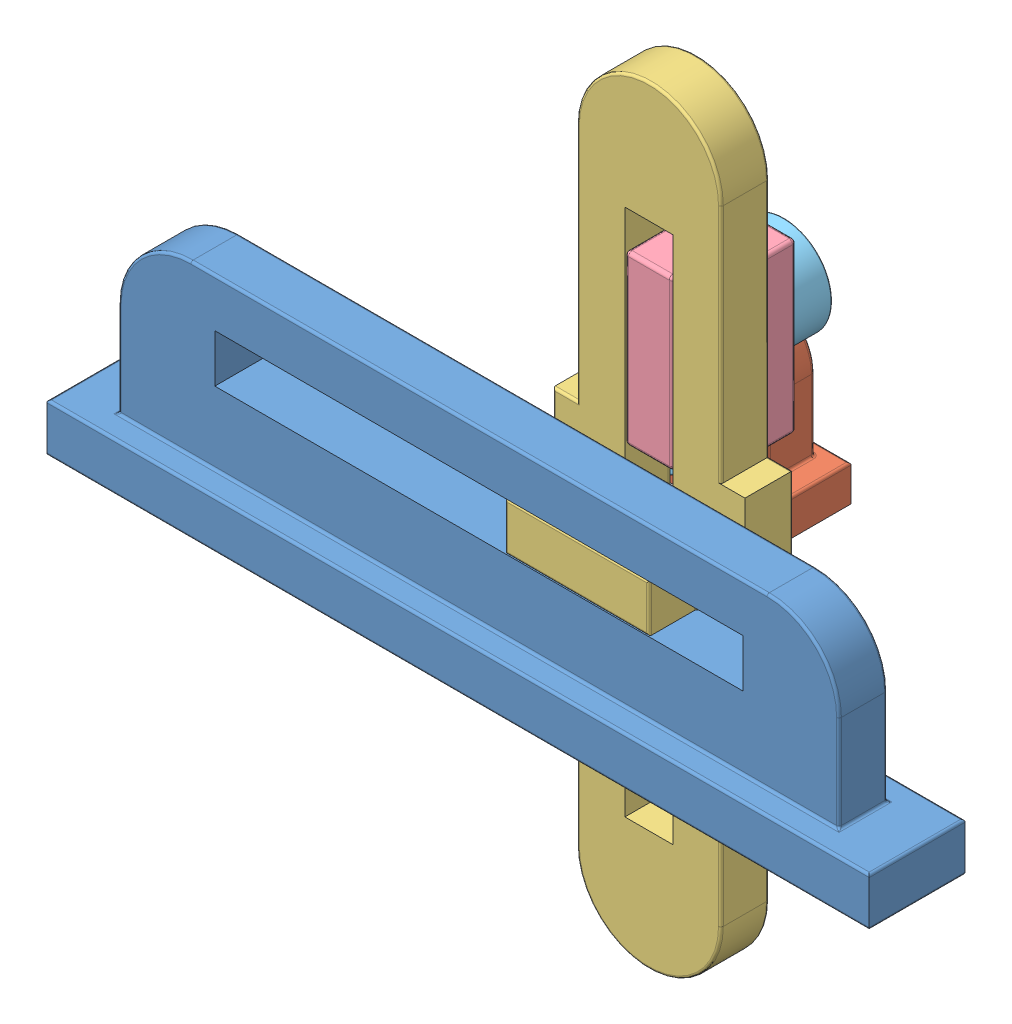
SolidWorks assembly SliderCrank, configuration Default. Lengths in mm.
Overall size (342.57 320 135).
6 component instances, 6 part files, 15 mates.
Components (placement in the parent):
- Slider Body-2: Slider Body [Default] at (60 35 -10) x (1 0 0) z (0 -1 0) size (342.57 40 90)
- Rotor-2: Rotor [Default] at (140 15 -85) x (1 0 0) z (0 -1 0) size (60 30 65)
- Slider-1: Slider [Default] at (210.8163 175 -40) size (80 320 50)
- Connector-2: Connector [Default] at (232.1496 104.3288 -60) x (-1 0 0) z (0 0 -1) size (50 70 60)
- Connecting-rod-2: Connecting-rod [Default] at (207.1496 104.3288 -70) x (0.847554 -0.530708 0) z (0 0 1) size (40 110 20)
- Connecting-Pin-1: Connecting-Pin [Default] at (170 45 -110) x (1 0 0) z (0 -1 0) size (20 50 20)
Mates (geometry in assembly coordinates):
- Coincident2: coincident: plane of Slider Body-2 through (60 35 0) normal (0 0 -1); plane of assembly through (0 0 0) normal (0 0 1)
- Coincident3: coincident: plane of Slider Body-2 through (60 0 -10) normal (0 1 0); plane of assembly through (0 0 0) normal (0 1 0)
- Coincident4: coincident: plane of Slider Body-2 through (0 -15 20) normal (-1 0 0); plane of assembly through (0 0 0) normal (1 0 0)
- Coincident15: coincident: plane of Rotor-2 through (140 0 -85) normal (0 -1 0); plane of assembly through (0 0 0) normal (0 1 0)
- Coincident16: coincident: plane of Slider Body-2 through (170 35 -10) normal (-1 0 0); axis of Rotor-2 through (170 45 -91.5) axis (0 0 -1)
- Coincident17: coincident: plane of Slider Body-2 through (50 45 10) normal (0 0 1); plane of Slider-1 through (210.8163 175 10) normal (0 0 1)
- Coincident18: coincident: plane of Slider Body-2 through (60 55 10) normal (0 -1 0); plane of Slider-1 through (180.8163 55 10) normal (0 1 0)
- Coincident19: coincident: plane of Slider-1 through (210.8163 175 -20) normal (0 0 1); plane of Connector-2 through (220.8163 139.3288 -20) normal (0 0 1)
- Coincident20: coincident: plane of Slider-1 through (200.8163 -65 -20) normal (1 0 0); plane of Connector-2 through (200.8163 139.3288 -20) normal (-1 0 0)
- Coincident21: coincident: plane of Connector-2 through (207.1496 104.3288 -80) normal (0 0 -1); plane of Connecting-rod-2 through (207.1496 104.3288 -80) normal (0 0 -1)
- Concentric1: concentric: cylinder of Connector-2 through (207.1496 104.3288 -80) axis (0 0 1) radius 10; cylinder of Connecting-rod-2 through (207.1496 104.3288 -60) axis (0 0 -1) radius 10
- Coincident22: coincident: plane of Connecting-rod-2 through (207.1496 104.3288 -60) normal (0 0 1); plane of Connecting-Pin-1 through (170 45 -60) normal (0 0 1)
- Concentric2: concentric: cylinder of Connecting-rod-2 through (170 45 -60) axis (0 0 -1) radius 10; cylinder of Connecting-Pin-1 through (170 45 -60) axis (0 0 -1) radius 10
- Concentric3: concentric: cylinder of Rotor-2 through (170 45 -90) axis (0 0 -1) radius 10; cylinder of Connecting-Pin-1 through (170 45 -60) axis (0 0 -1) radius 10
- Concentric4: concentric: cylinder of Connector-2 through (102.2988 62.7918 -80) axis (0 0 1) radius 10; cylinder of Connecting-rod-2 through (102.2988 62.7918 -60) axis (0 0 -1) radius 10
